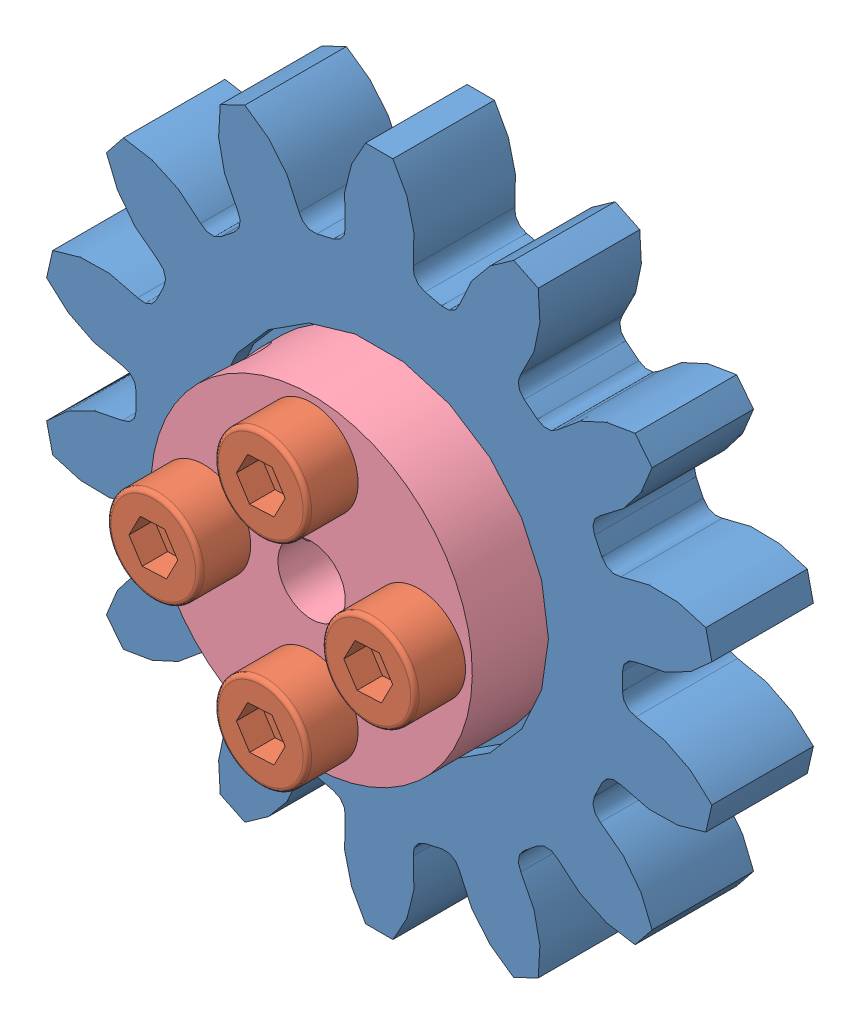
SolidWorks assembly engrenage-complet, configuration Défaut. Lengths in mm.
Overall size (39.32 40 13).
10 component instances, 4 part files, 23 mates.
Components (placement in the parent):
- engrenage-1: engrenage [Défaut] at (1.0609 0.1936 0) size (39.32 40 6)
- vis-chc-2: vis-chc [Vis CHC M3x10] at (6.0322 -0.3667 10) x (0.997256 0.074024 0) z (0.074024 -0.997256 0) size (5.5 13 5.5)
- ecrou-h-1: ecrou-h [6012 HU M3] at (6.0322 -0.3667 0.1) x (1 0 0) z (0 1 0) size (5.5 2.4 6.35)
- engrenage-moyeu-1: engrenage-moyeu [Défaut] at (-0.3178 -0.3667 7.5) x (0.707107 -0.707107 0) z (0 0 1) size (19 19 5)
- vis-chc-3: vis-chc [Vis CHC M3x10] at (-0.3178 5.9833 10) x (0.997256 0.074024 0) z (0.074024 -0.997256 0) size (5.5 13 5.5)
- vis-chc-4: vis-chc [Vis CHC M3x10] at (-6.6678 -0.3667 10) x (0.997256 0.074024 0) z (0.074024 -0.997256 0) size (5.5 13 5.5)
- vis-chc-5: vis-chc [Vis CHC M3x10] at (-0.3178 -6.7167 10) x (0.997256 0.074024 0) z (0.074024 -0.997256 0) size (5.5 13 5.5)
- ecrou-h-2: ecrou-h [6012 HU M3] at (-6.6678 -0.3667 0.1) x (0.5 0.866025 0) z (-0.866025 0.5 0) size (5.5 2.4 6.35)
- ecrou-h-3: ecrou-h [6012 HU M3] at (-0.3178 5.9833 0.1) x (0.866025 0.5 0) z (-0.5 0.866025 0) size (5.5 2.4 6.35)
- ecrou-h-4: ecrou-h [6012 HU M3] at (-0.3178 -6.7167 0.1) x (0.866025 0.5 0) z (-0.5 0.866025 0) size (5.5 2.4 6.35)
Mates (geometry in assembly coordinates):
- Coaxiale3: concentric anti-aligned: cylinder of vis-chc-2 through (6.0322 -0.3667 0) axis (0 0 1) radius 1.5; cylinder of ecrou-h-1 through (6.0322 -0.3667 2.5) axis (0 0 -1) radius 1.2295
- Parallèle1: parallel: line of engrenage-1 through (3.5 3.0011 1.3833) axis (0 0.866025 0.5); plane of ecrou-h-1 through (3.2822 1.221 2.5) normal (-0.5 0.866025 0)
- Coïncidente14: coincident anti-aligned: plane of engrenage-1 through (1.0609 0.1936 2.5) normal (0 0 -1); plane of ecrou-h-1 through (8.7822 -1.9544 2.5) normal (0 0 1)
- Coaxiale5: concentric anti-aligned: cylinder of engrenage-1 through (-0.3178 -0.3667 0) axis (0 0 1) radius 2.15; cylinder of engrenage-moyeu-1 through (-0.3178 -0.3667 10) axis (0 0 -1) radius 2
- Coïncidente15: coincident anti-aligned: plane of engrenage-1 through (-0.3178 -0.3667 5) normal (0 0 1); plane of engrenage-moyeu-1 through (-0.3178 -0.3667 5) normal (0 0 -1)
- Coaxiale6: concentric anti-aligned: cylinder of vis-chc-2 through (6.0322 -0.3667 0) axis (0 0 1) radius 1.5; cylinder of engrenage-moyeu-1 through (6.0322 -0.3667 10) axis (0 0 -1) radius 1.5
- Coïncidente16: coincident anti-aligned: plane of vis-chc-2 through (6.0322 -0.3667 10) normal (0 0 -1); plane of engrenage-moyeu-1 through (-0.3178 -0.3667 10) normal (0 0 1)
- Coaxiale7: concentric aligned: cylinder of engrenage-1 through (6.0322 -0.3667 0) axis (0 0 1) radius 1.6; cylinder of vis-chc-2 through (6.0322 -0.3667 0) axis (0 0 1) radius 1.5
- Coaxiale8: concentric anti-aligned: cylinder of engrenage-1 through (-0.3178 -6.7167 0) axis (0 0 1) radius 1.6; cylinder of ecrou-h-4 through (-0.3178 -6.7167 2.5) axis (0 0 -1) radius 1.2295
- Coaxiale9: concentric anti-aligned: cylinder of engrenage-1 through (-6.6678 -0.3667 0) axis (0 0 1) radius 1.6; cylinder of ecrou-h-2 through (-6.6678 -0.3667 2.5) axis (0 0 -1) radius 1.2295
- Coaxiale10: concentric anti-aligned: cylinder of engrenage-1 through (-0.3178 5.9833 0) axis (0 0 1) radius 1.6; cylinder of ecrou-h-3 through (-0.3178 5.9833 2.5) axis (0 0 -1) radius 1.2295
- Parallèle2: parallel anti-aligned: plane of engrenage-1 through (-2.0678 -3.6856 2.5) normal (0 -1 0); plane of ecrou-h-4 through (-1.9055 -3.9667 2.5) normal (0 1 0)
- Parallèle3: parallel anti-aligned: plane of engrenage-1 through (-9.6989 1.3833 2.5) normal (0.5 -0.866025 0); plane of ecrou-h-2 through (-9.4178 1.221 2.5) normal (-0.5 0.866025 0)
- Parallèle4: parallel anti-aligned: plane of engrenage-1 through (3.1822 5.9833 2.5) normal (-0.866025 0.5 0); plane of ecrou-h-3 through (2.8576 5.9833 2.5) normal (0.866025 -0.5 0)
- Coïncidente20: coincident anti-aligned: plane of engrenage-1 through (1.0609 0.1936 2.5) normal (0 0 -1); plane of ecrou-h-3 through (2.8576 5.9833 2.5) normal (0 0 1)
- Coïncidente21: coincident anti-aligned: plane of engrenage-1 through (1.0609 0.1936 2.5) normal (0 0 -1); plane of ecrou-h-2 through (-3.9178 1.221 2.5) normal (0 0 1)
- Coïncidente22: coincident anti-aligned: plane of engrenage-1 through (1.0609 0.1936 2.5) normal (0 0 -1); plane of ecrou-h-4 through (2.8576 -6.7167 2.5) normal (0 0 1)
- Coaxiale11: concentric anti-aligned: cylinder of engrenage-moyeu-1 through (-0.3178 -6.7167 10) axis (0 0 -1) radius 1.5; cylinder of vis-chc-5 through (-0.3178 -6.7167 0) axis (0 0 1) radius 1.5
- Coïncidente23: coincident anti-aligned: plane of engrenage-moyeu-1 through (-0.3178 -0.3667 10) normal (0 0 1); plane of vis-chc-5 through (-0.3178 -6.7167 10) normal (0 0 -1)
- Coaxiale12: concentric anti-aligned: cylinder of engrenage-moyeu-1 through (-6.6678 -0.3667 10) axis (0 0 -1) radius 1.5; cylinder of vis-chc-4 through (-6.6678 -0.3667 0) axis (0 0 1) radius 1.5
- Coaxiale13: concentric anti-aligned: cylinder of engrenage-moyeu-1 through (-0.3178 5.9833 10) axis (0 0 -1) radius 1.5; cylinder of vis-chc-3 through (-0.3178 5.9833 0) axis (0 0 1) radius 1.5
- Coïncidente24: coincident anti-aligned: plane of engrenage-moyeu-1 through (-0.3178 -0.3667 10) normal (0 0 1); plane of vis-chc-4 through (-6.6678 -0.3667 10) normal (0 0 -1)
- Coïncidente25: coincident anti-aligned: plane of engrenage-moyeu-1 through (-0.3178 -0.3667 10) normal (0 0 1); plane of vis-chc-3 through (-0.3178 5.9833 10) normal (0 0 -1)
